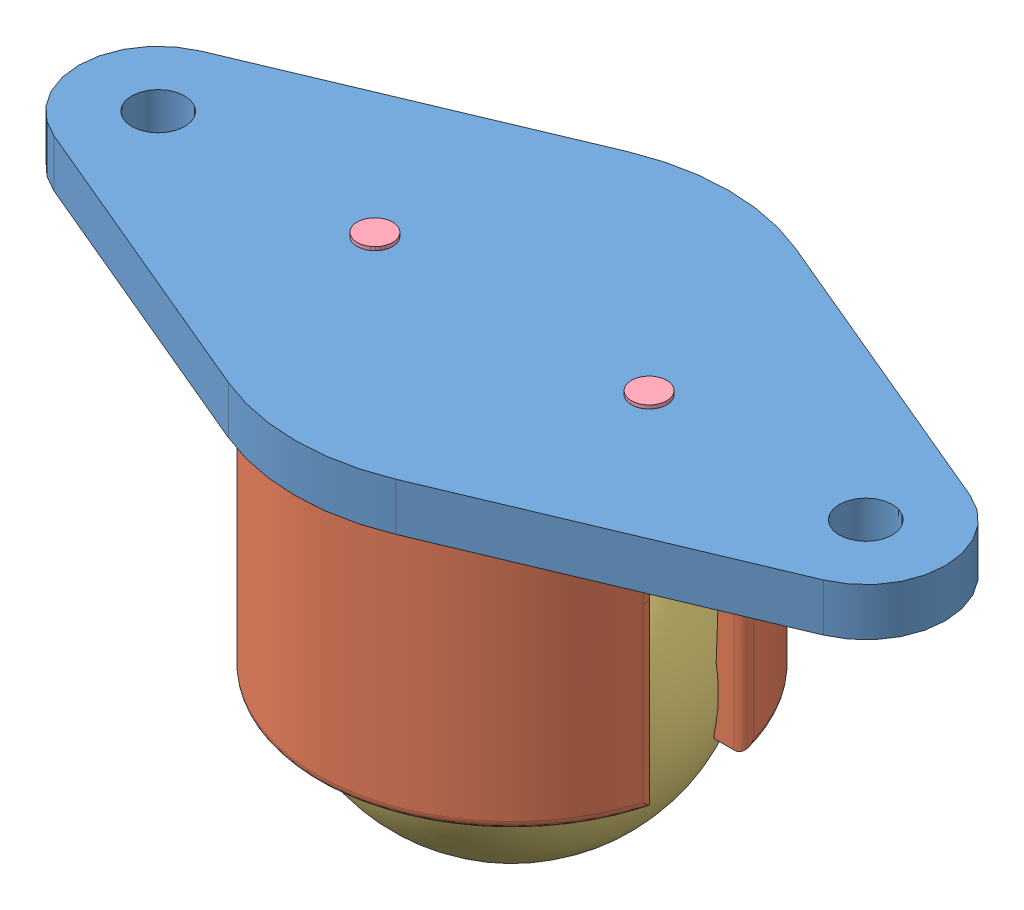
SolidWorks assembly Caster, configuration Default. Lengths in mm.
Overall size (49 30.1 27.68).
5 component instances, 4 part files, 9 mates.
Components (placement in the parent):
- Caster Bracket-1: Caster Bracket [Default] at (1.2214 5.2442 -5.1245) size (49 2.7 24.5)
- Ball Housing-2: Ball Housing [Default] at (1.2214 5.2442 -5.1245) x (1 0 0) z (0 0 -1) size (22 14.84 22)
- Steel Ball-1: Steel Ball [Default] at (1.2214 -7.2558 -5.1245) x (0.569673 0.341131 0.747732) z (-0.467558 0.882738 -0.046507) size (19 19 19)
- pan head cross recess screw_iso-2: pan head cross recess screw_iso [ISO 7045 - M2 x 5 - Z --- 5C] at (-6.5286 1.5442 -5.1245) x (0 1 0) z (-0.998629 0 -0.052354) size (6.57 4 4)
- pan head cross recess screw_iso-3: pan head cross recess screw_iso [ISO 7045 - M2 x 5 - Z --- 5C] at (8.9714 1.5442 -5.1245) x (0 1 0) z (0.912149 0 0.40986) size (6.57 4 4)
Mates (geometry in assembly coordinates):
- Concentric1: concentric aligned: cylinder of Caster Bracket-1 through (-6.5286 5.2432 -5.1245) axis (0 1 0) radius 1; cylinder of Ball Housing-2 through (-6.5286 -9.5568 -5.1245) axis (0 1 0) radius 1
- Concentric2: concentric aligned: cylinder of Caster Bracket-1 through (8.9714 5.2432 -5.1245) axis (0 1 0) radius 1; cylinder of Ball Housing-2 through (8.9714 -9.5568 -5.1245) axis (0 1 0) radius 1
- Coincident1: coincident anti-aligned: plane of Caster Bracket-1 through (1.2214 5.2442 -5.1245) normal (0 -1 0); plane of Ball Housing-2 through (1.2214 5.2442 -5.1245) normal (0 1 0)
- Distance1: distance = 0.9 mm anti-aligned: sphere of Steel Ball-1; plane of Ball Housing-2 through (1.2214 3.1442 -5.1245) normal (0 -1 0)
- Concentric4: concentric: cylinder of Ball Housing-2 through (1.2214 5.2452 -5.1245) axis (0 -1 0) radius 5.5; sphere of Steel Ball-1
- Concentric5: concentric anti-aligned: cylinder of Ball Housing-2 through (-6.5286 -9.5568 -5.1245) axis (0 1 0) radius 1; cylinder of pan head cross recess screw_iso-2 through (-6.5286 -23.8558 -5.1245) axis (0 -1 0) radius 1
- Coincident3: coincident anti-aligned: plane of Ball Housing-2 through (1.2214 3.1442 -5.1245) normal (0 -1 0); plane of pan head cross recess screw_iso-2 through (-6.4763 3.1442 -6.1231) normal (0 1 0)
- Concentric6: concentric anti-aligned: cylinder of Ball Housing-2 through (8.9714 -9.5568 -5.1245) axis (0 1 0) radius 1; cylinder of pan head cross recess screw_iso-3 through (8.9714 -23.8558 -5.1245) axis (0 -1 0) radius 1
- Coincident4: coincident anti-aligned: plane of Ball Housing-2 through (1.2214 3.1442 -5.1245) normal (0 -1 0); plane of pan head cross recess screw_iso-3 through (8.5615 3.1442 -4.2123) normal (0 1 0)
